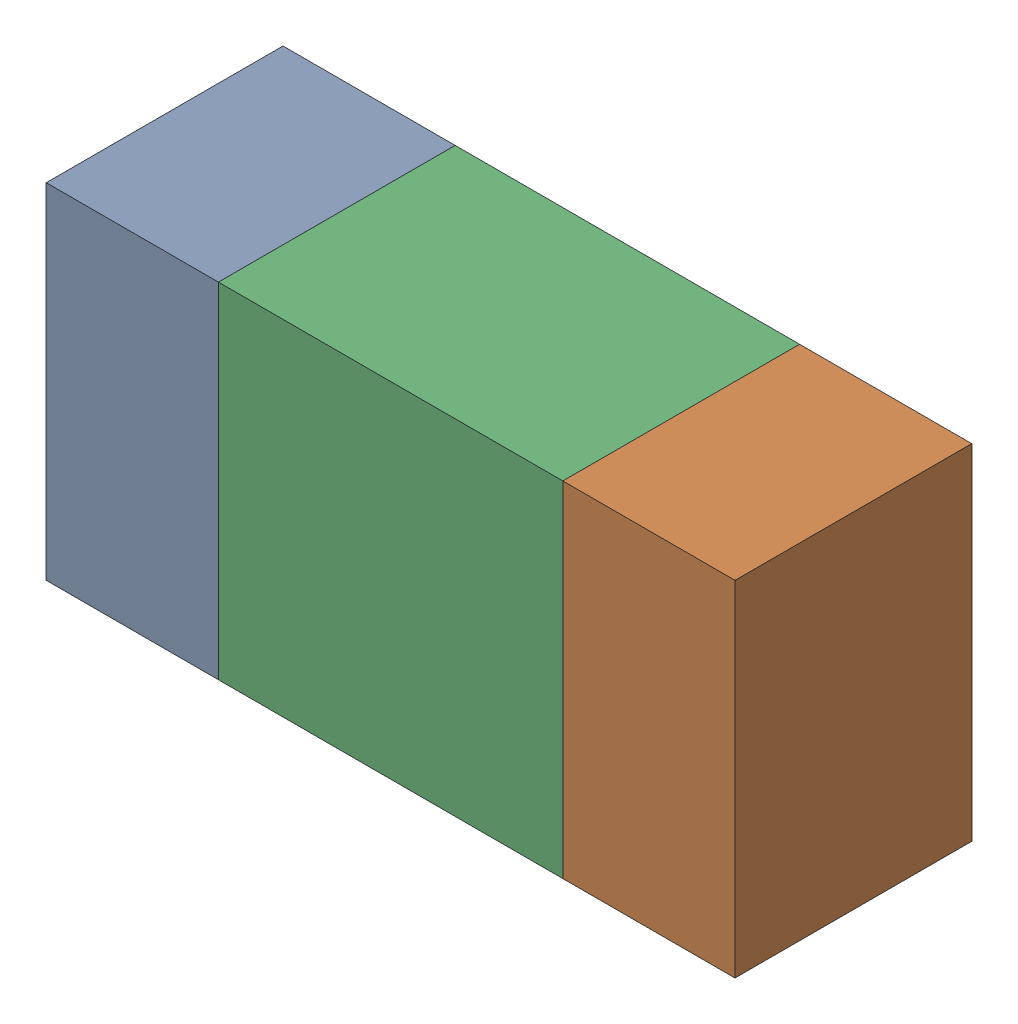
SolidWorks assembly R68, configuration ﾃﾞﾌｫﾙﾄ. Lengths in mm.
Overall size (1.6 0.8 0.55).
6 component instances, 2 part files, 0 mates.
Components (placement in the parent):
- 689261512-1: 689261512 [ﾃﾞﾌｫﾙﾄ] at (10.6501 60.7499 -1.7503) size (0.4 0.8 0.55)
  - Extruded_32-1: Extruded_32 [ﾃﾞﾌｫﾙﾄ] at origin size (0.4 0.8 0.55)
- 689261512-2: 689261512 [ﾃﾞﾌｫﾙﾄ] at (11.8501 60.7499 -1.7503) size (0.4 0.8 0.55)
  - Extruded_32-1: Extruded_32 [ﾃﾞﾌｫﾙﾄ] at origin size (0.4 0.8 0.55)
- 689261648-1: 689261648 [ﾃﾞﾌｫﾙﾄ] at (11.25 60.7499 -1.7503) size (0.8 0.8 0.55)
  - Extruded_33-1: Extruded_33 [ﾃﾞﾌｫﾙﾄ] at origin size (0.8 0.8 0.55)
